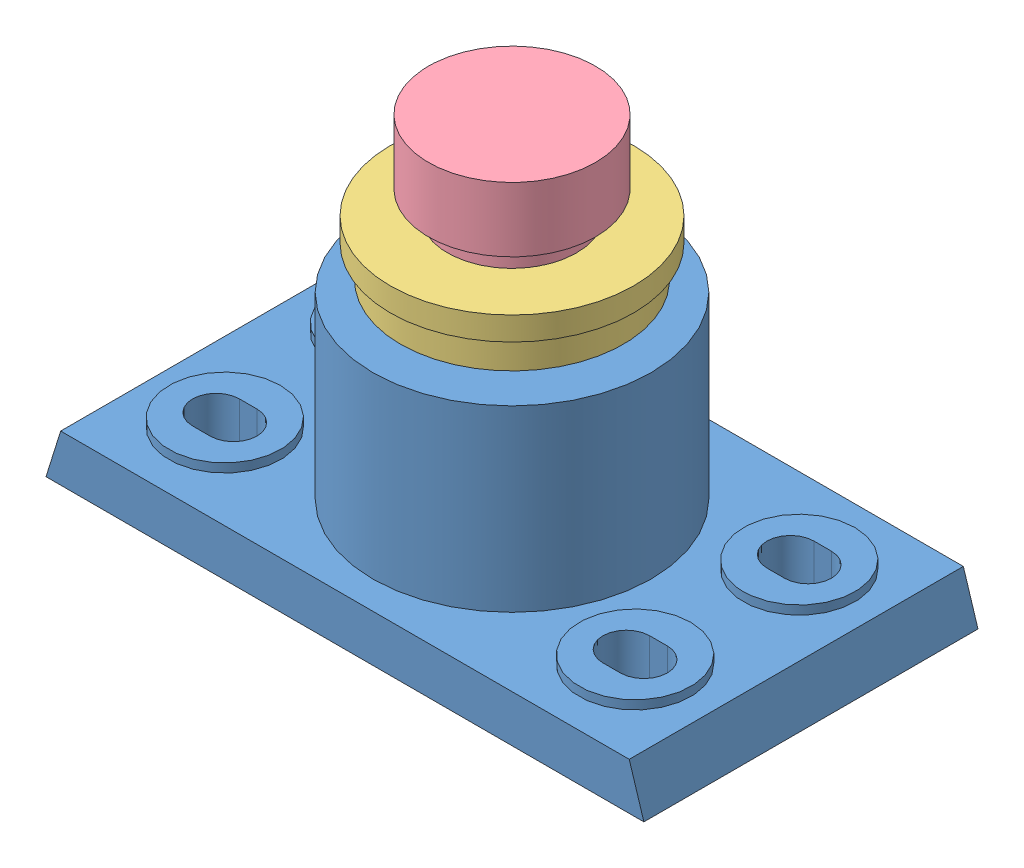
SolidWorks assembly Assem1, configuration Default. Lengths in mm.
Overall size (204 129.59 114).
4 component instances, 4 part files, 6 mates.
Components (placement in the parent):
- caitypinholelong-1: caitypinholelong [Default] at (79.2371 68.4444 154.6271) size (204 77 114)
- cavityforpinholehalf-1: cavityforpinholehalf [Default] at (79.2371 84.4444 154.6271) size (44 13 44)
- bush-1: bush [Default] at (79.2371 84.4444 154.6271) size (83 83.62 83)
- shaft-1: shaft [Default] at (79.2371 176.0368 154.6271) x (1 0 0) z (0 -1 0) size (57 57 97)
Mates (geometry in assembly coordinates):
- Parallel1: parallel anti-aligned: plane of caitypinholelong-1 through (176.2371 84.4444 211.6271) normal (0 1 0); plane of cavityforpinholehalf-1 through (79.2371 84.4444 154.6271) normal (0 -1 0)
- Coincident4: coincident anti-aligned: plane of caitypinholelong-1 through (176.2371 84.4444 211.6271) normal (0 1 0); plane of cavityforpinholehalf-1 through (79.2371 84.4444 154.6271) normal (0 -1 0)
- Concentric1: concentric aligned: circle of caitypinholelong-1; cylinder of cavityforpinholehalf-1 through (79.2371 117.8752 154.6271) axis (0 1 0) radius 22
- Coincident6: coincident: plane of caitypinholelong-1 through (176.2371 84.4444 211.6271) normal (0 1 0); plane of bush-1 through (101.2371 84.4444 154.6271) normal (0 -1 0)
- Concentric5: concentric anti-aligned: cylinder of caitypinholelong-1 through (79.2371 97.4444 154.6271) axis (0 1 0) radius 32.5; cylinder of bush-1 through (79.2371 9.7771 154.6271) axis (0 -1 0) radius 29.5
- Concentric6: concentric anti-aligned: cylinder of bush-1 through (79.2371 9.7771 154.6271) axis (0 -1 0) radius 22; cylinder of shaft-1 through (79.2371 101.0368 154.6271) axis (0 1 0) radius 22
